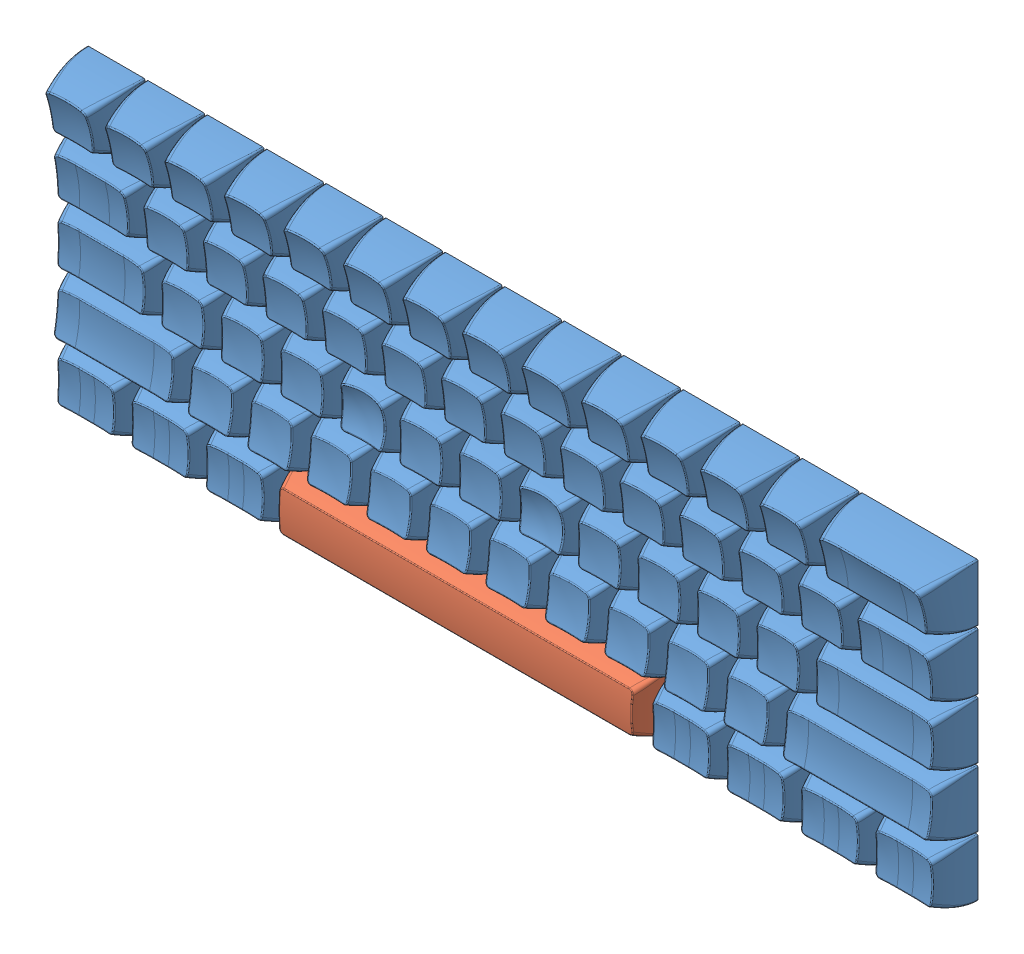
SolidWorks assembly SA_60%, configuration Default. Lengths in mm.
Overall size (285.53 94.62 17.52).
61 component instances, 2 part files, 36 mates.
Components (placement in the parent):
- sa-20: sa [R1] at origin size (18.77 18.42 17.52)
- sa-21: sa [R1] at (19.05 0 0) size (18.77 18.42 17.52)
- sa-22: sa [R1] at (38.1 0 0) size (18.77 18.42 17.52)
- sa-23: sa [R1] at (57.15 0 0) size (18.77 18.42 17.52)
- sa-24: sa [R1] at (76.2 0 0) size (18.77 18.42 17.52)
- sa-25: sa [R1] at (95.25 0 0) size (18.77 18.42 17.52)
- sa-26: sa [R1] at (114.3 0 0) size (18.77 18.42 17.52)
- sa-27: sa [R1] at (133.35 0 0) size (18.77 18.42 17.52)
- sa-28: sa [R1] at (152.4 0 0) size (18.77 18.42 17.52)
- sa-29: sa [R1] at (171.45 0 0) size (18.77 18.42 17.52)
- sa-30: sa [R1] at (190.5 0 0) size (18.77 18.42 17.52)
- sa-31: sa [R1] at (209.55 0 0) size (18.77 18.42 17.52)
- sa-32: sa [R1] at (228.6 0 0) size (18.77 18.42 17.52)
- sa-33: sa [R1_100x200] at (257.175 0 0) size (37.82 18.42 17.52)
- sa-34: sa [R2_100x150] at (4.7625 -19.05 0) size (28.03 18.42 13.86)
- sa-35: sa [R2_100x100] at (28.575 -19.05 0) size (18.5 18.42 13.86)
- sa-36: sa [R2_100x100] at (47.625 -19.05 0) size (18.5 18.42 13.86)
- sa-37: sa [R2_100x100] at (66.675 -19.05 0) size (18.5 18.42 13.86)
- sa-38: sa [R2_100x100] at (85.725 -19.05 0) size (18.5 18.42 13.86)
- sa-39: sa [R2_100x100] at (104.775 -19.05 0) size (18.5 18.42 13.86)
- sa-40: sa [R2_100x100] at (123.825 -19.05 0) size (18.5 18.42 13.86)
- sa-41: sa [R2_100x100] at (142.875 -19.05 0) size (18.5 18.42 13.86)
- sa-42: sa [R2_100x100] at (161.925 -19.05 0) size (18.5 18.42 13.86)
- sa-43: sa [R2_100x100] at (180.975 -19.05 0) size (18.5 18.42 13.86)
- sa-44: sa [R2_100x100] at (200.025 -19.05 0) size (18.5 18.42 13.86)
- sa-45: sa [R2_100x100] at (219.075 -19.05 0) size (18.5 18.42 13.86)
- sa-46: sa [R2_100x100] at (238.125 -19.05 0) size (18.5 18.42 13.86)
- sa-47: sa [R2_100x150] at (261.9375 -19.05 0) size (28.03 18.42 13.86)
- sa-48: sa [R3_100x175] at (7.1437 -38.1 0) size (32.79 18.42 13.79)
- sa-49: sa [R3_100x100] at (33.3375 -38.1 0) size (18.5 18.42 13.79)
- sa-61: sa [R3_100x100] at (52.3875 -38.1 0) size (18.5 18.42 13.79)
- sa-62: sa [R3_100x100] at (71.4375 -38.1 0) size (18.5 18.42 13.79)
- sa-63: sa [R3_100x100_homing] at (90.4875 -38.1 0) size (18.5 18.42 13.1)
- sa-64: sa [R3_100x100] at (109.5375 -38.1 0) size (18.5 18.42 13.79)
- sa-65: sa [R3_100x100] at (128.5875 -38.1 0) size (18.5 18.42 13.79)
- sa-66: sa [R3_100x100_homing] at (147.6375 -38.1 0) size (18.5 18.42 13.1)
- sa-67: sa [R3_100x100] at (166.6875 -38.1 0) size (18.5 18.42 13.79)
- sa-68: sa [R3_100x100] at (185.7375 -38.1 0) size (18.5 18.42 13.79)
- sa-69: sa [R3_100x100] at (204.7875 -38.1 0) size (18.5 18.42 13.79)
- sa-70: sa [R3_100x100] at (223.8375 -38.1 0) size (18.5 18.42 13.79)
- sa-71: sa [R3_100x225] at (254.7937 -38.1 0) size (42.31 18.42 13.79)
- sa-72: sa [R4_100x225] at (11.9062 -57.15 0) size (42.64 18.42 13.87)
- sa-73: sa [R4_100x100] at (42.8625 -57.15 0) size (18.5 18.42 13.87)
- sa-74: sa [R4_100x100] at (61.9125 -57.15 0) size (18.5 18.42 13.87)
- sa-75: sa [R4_100x100] at (80.9625 -57.15 0) size (18.5 18.42 13.87)
- sa-76: sa [R4_100x100] at (100.0125 -57.15 0) size (18.5 18.42 13.87)
- sa-77: sa [R4_100x100] at (119.0625 -57.15 0) size (18.5 18.42 13.87)
- sa-78: sa [R4_100x100] at (138.1125 -57.15 0) size (18.5 18.42 13.87)
- sa-79: sa [R4_100x100] at (157.1625 -57.15 0) size (18.5 18.42 13.87)
- sa-80: sa [R4_100x100] at (176.2125 -57.15 0) size (18.5 18.42 13.87)
- sa-81: sa [R4_100x100] at (195.2625 -57.15 0) size (18.5 18.42 13.87)
- sa-82: sa [R4_100x100] at (214.3125 -57.15 0) size (18.5 18.42 13.87)
- sa-83: sa [R4_100x275] at (250.0312 -57.15 0) size (52.17 18.42 13.87)
- sa-84: sa [R3_100x125] at (2.3813 -76.2 0) size (23.26 18.42 13.79)
- sa-85: sa [R3_100x125] at (26.1937 -76.2 0) size (23.26 18.42 13.79)
- sa-86: sa [R3_100x125] at (50.0063 -76.2 0) size (23.26 18.42 13.79)
- sa-87: sa [R3_100x125] at (192.8812 -76.2 0) size (23.26 18.42 13.79)
- sa-88: sa [R3_100x125] at (216.6937 -76.2 0) size (23.26 18.42 13.79)
- sa-89: sa [R3_100x125] at (240.5062 -76.2 0) size (23.26 18.42 13.79)
- sa-90: sa [R3_100x125] at (264.3187 -76.2 0) size (23.26 18.42 13.79)
- sa_space-2: sa_space [sa_R3_100x625_space] at (121.4438 -76.2 0) size (118.42 18.41 14.01)
Mates (geometry in assembly coordinates):
- Distance1: distance = 28.575 mm aligned: plane of sa-32 through (228.6 0 0) normal (1 0 0); plane of sa-33 through (257.175 0 0) normal (1 0 0)
- Coincident27: coincident aligned: plane of sa-20 through (0 0 0) normal (0 0 -1); plane of sa-33 through (257.175 0 0) normal (0 0 -1)
- Coincident28: coincident aligned: plane of sa-20 through (0 0 0) normal (0 1 0); plane of sa-33 through (257.175 0 0) normal (0 1 0)
- Coincident29: coincident aligned: plane of sa-20 through (0 0 0) normal (0 0 -1); plane of sa-34 through (4.7625 -19.05 0) normal (0 0 -1)
- Distance2: distance = 19.05 mm aligned: plane of sa-34 through (4.7625 -19.05 0) normal (0 1 0); plane of sa-20 through (0 0 0) normal (0 1 0)
- Distance3: distance = 4.7625 mm aligned: plane of sa-20 through (0 0 0) normal (1 0 0); plane of sa-34 through (4.7625 -19.05 0) normal (1 0 0)
- Coincident30: coincident aligned: plane of sa-20 through (0 0 0) normal (0 0 -1); plane of sa-35 through (28.575 -19.05 0) normal (0 0 -1)
- Coincident31: coincident aligned: plane of sa-34 through (4.7625 -19.05 0) normal (0 1 0); plane of sa-35 through (28.575 -19.05 0) normal (0 1 0)
- Distance4: distance = 23.8125 mm aligned: plane of sa-35 through (28.575 -19.05 0) normal (1 0 0); plane of sa-34 through (4.7625 -19.05 0) normal (1 0 0)
- Coincident32: coincident aligned: plane of sa-20 through (0 0 0) normal (0 0 -1); plane of sa-47 through (261.9375 -19.05 0) normal (0 0 -1)
- Coincident33: coincident aligned: plane of sa-34 through (4.7625 -19.05 0) normal (0 1 0); plane of sa-47 through (261.9375 -19.05 0) normal (0 1 0)
- Distance5: distance = 23.8125 mm aligned: plane of sa-47 through (261.9375 -19.05 0) normal (1 0 0); plane of sa-46 through (238.125 -19.05 0) normal (1 0 0)
- Coincident34: coincident aligned: plane of sa-20 through (0 0 0) normal (0 0 -1); plane of sa-48 through (7.1437 -38.1 0) normal (0 0 -1)
- Distance6: distance = 19.05 mm aligned: plane of sa-34 through (4.7625 -19.05 0) normal (0 1 0); plane of sa-48 through (7.1437 -38.1 0) normal (0 1 0)
- Distance7: distance = 7.1437 mm aligned: plane of sa-20 through (0 0 0) normal (1 0 0); plane of sa-48 through (7.1437 -38.1 0) normal (1 0 0)
- Coincident35: coincident aligned: plane of sa-20 through (0 0 0) normal (0 0 -1); plane of sa-49 through (33.3375 -38.1 0) normal (0 0 -1)
- Coincident36: coincident aligned: plane of sa-48 through (7.1437 -38.1 0) normal (0 1 0); plane of sa-49 through (33.3375 -38.1 0) normal (0 1 0)
- Distance8: distance = 26.1937 mm aligned: plane of sa-48 through (7.1437 -38.1 0) normal (1 0 0); plane of sa-49 through (33.3375 -38.1 0) normal (1 0 0)
- Coincident37: coincident aligned: plane of sa-20 through (0 0 0) normal (0 0 -1); plane of sa-71 through (254.7937 -38.1 0) normal (0 0 -1)
- Coincident38: coincident aligned: plane of sa-48 through (7.1437 -38.1 0) normal (0 1 0); plane of sa-71 through (254.7937 -38.1 0) normal (0 1 0)
- Distance9: distance = 30.9563 mm aligned: plane of sa-70 through (223.8375 -38.1 0) normal (1 0 0); plane of sa-71 through (254.7937 -38.1 0) normal (1 0 0)
- Coincident39: coincident aligned: plane of sa-20 through (0 0 0) normal (0 0 -1); plane of sa-72 through (11.9062 -57.15 0) normal (0 0 -1)
- Distance10: distance = 19.05 mm aligned: plane of sa-48 through (7.1437 -38.1 0) normal (0 1 0); plane of sa-72 through (11.9062 -57.15 0) normal (0 1 0)
- Distance11: distance = 11.9062 mm aligned: plane of sa-20 through (0 0 0) normal (1 0 0); plane of sa-72 through (11.9062 -57.15 0) normal (1 0 0)
- Coincident40: coincident aligned: plane of sa-20 through (0 0 0) normal (0 0 -1); plane of sa-73 through (42.8625 -57.15 0) normal (0 0 -1)
- Coincident41: coincident aligned: plane of sa-72 through (11.9062 -57.15 0) normal (0 1 0); plane of sa-73 through (42.8625 -57.15 0) normal (0 1 0)
- Distance12: distance = 30.9563 mm aligned: plane of sa-72 through (11.9062 -57.15 0) normal (1 0 0); plane of sa-73 through (42.8625 -57.15 0) normal (1 0 0)
- Coincident42: coincident aligned: plane of sa-72 through (11.9062 -57.15 0) normal (0 1 0); plane of sa-83 through (250.0312 -57.15 0) normal (0 1 0)
- Coincident43: coincident aligned: plane of sa-20 through (0 0 0) normal (0 0 -1); plane of sa-83 through (250.0312 -57.15 0) normal (0 0 -1)
- Distance13: distance = 35.7188 mm aligned: plane of sa-83 through (250.0312 -57.15 0) normal (1 0 0); plane of sa-82 through (214.3125 -57.15 0) normal (1 0 0)
- Coincident44: coincident aligned: plane of sa-20 through (0 0 0) normal (0 0 -1); plane of sa-84 through (2.3813 -76.2 0) normal (0 0 -1)
- Distance14: distance = 19.05 mm aligned: plane of sa-72 through (11.9062 -57.15 0) normal (0 1 0); plane of sa-84 through (2.3813 -76.2 0) normal (0 1 0)
- Distance15: distance = 2.3813 mm aligned: plane of sa-20 through (0 0 0) normal (1 0 0); plane of sa-84 through (2.3813 -76.2 0) normal (1 0 0)
- Coincident45: coincident aligned: plane of sa-20 through (0 0 0) normal (0 0 -1); plane of sa_space-2 through (121.4438 -76.2 0) normal (0 0 -1)
- Coincident46: coincident aligned: plane of sa-84 through (2.3813 -76.2 0) normal (0 1 0); plane of sa_space-2 through (121.4438 -76.2 0) normal (0 1 0)
- Distance16: distance = 119.0625 mm aligned: plane of sa_space-2 through (121.4438 -76.2 0) normal (1 0 0); plane of sa-84 through (2.3813 -76.2 0) normal (1 0 0)
